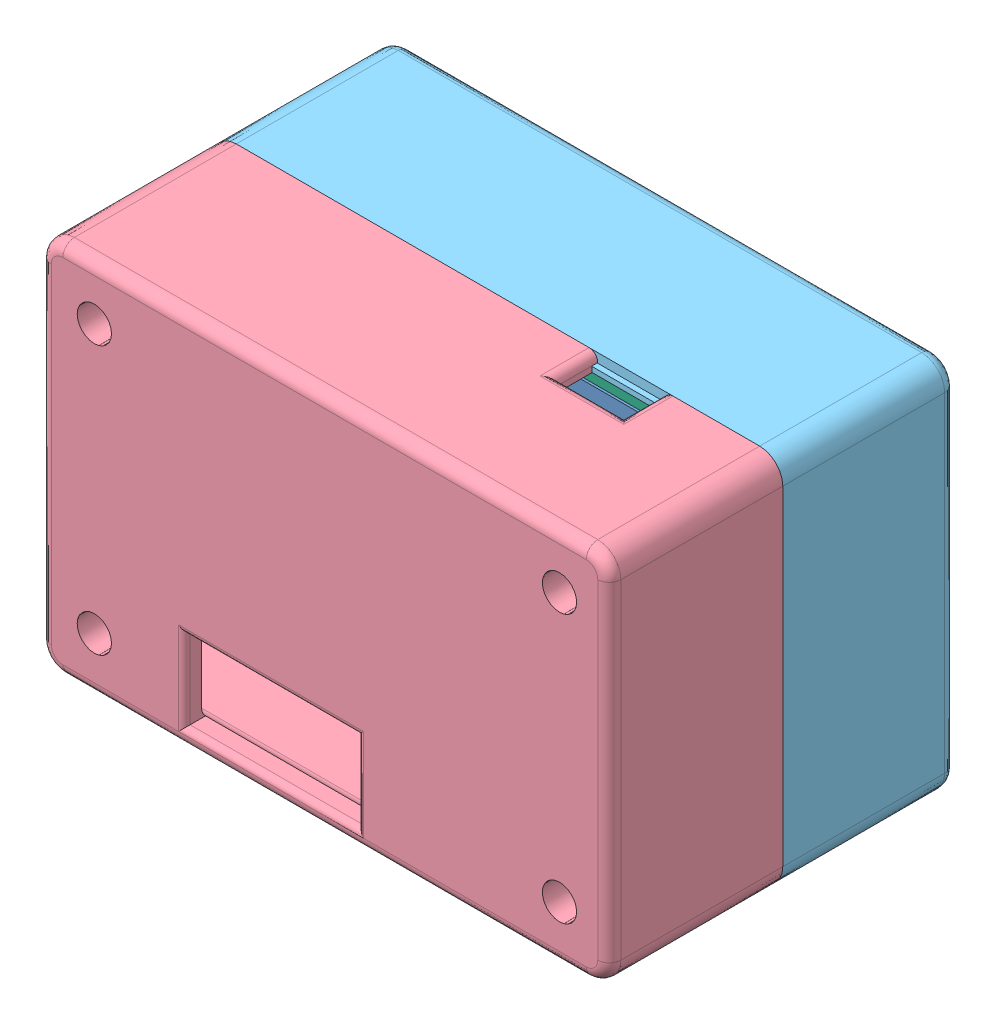
SolidWorks assembly final, configuration Default. Lengths in mm.
Overall size (268.32 64.99 60).
189 component instances, 44 part files, 14 mates.
Components (placement in the parent):
- PCB1.step-1: PCB1.step [Default] at origin size (88.64 54.99 37.9)
  - Board.step-1: Board.step [Default] at origin size (88.64 54.99 0.41)
    - Open CASCADE STEP translator 6.8 1.1.1.step-1: Open CASCADE STEP translator 6.8 1.1.1.step [Default] at (0 0 -0.4115) size (88.64 54.99 0.41)
  - J3.step-1: J3.step [Default] at origin size (11.2 7.5 13.4)
    - 691102710002.step-1: 691102710002.step [Default] at (107.7229 115.096 5.01) x (-1 0 0) z (0 0 1) size (11.2 7.5 13.4)
      - 691502710002.step-1: 691502710002.step [Default] at origin size (11.2 7.5 9.9)
      - 6911027100xx_CAGE.step-1: 6911027100xx_CAGE.step [Default] at (2.5 -0.45 -1.75) size (4 4 9.05)
      - 6911027100xx_CAGE.step-2: 6911027100xx_CAGE.step [Default] at (-2.5 -0.45 -1.75) size (4 4 9.05)
      - 6911027100xx_PIN.step-1: 6911027100xx_PIN.step [Default] at (2.5 -0.45 -0.3503) size (3.9 5.3 2.5)
      - 6911027100xx_PIN.step-2: 6911027100xx_PIN.step [Default] at (-2.5 -0.45 -0.3503) size (3.9 5.3 2.5)
      - 6911027100xx_VIS.step-1: 6911027100xx_VIS.step [Default] at (2.5 -0.45 4.2) x (0 -1 0) z (0 0 1) size (3.5 3.5 5.3)
      - 6911027100xx_VIS.step-2: 6911027100xx_VIS.step [Default] at (-2.5 -0.45 4.2) x (0 -1 0) z (0 0 1) size (3.5 3.5 5.3)
  - Ths.step-1: Ths.step [Default] at origin size (6.6 6.99 9.5)
    - 6050182896.step-1: 6050182896.step [Default] at (65.386 72.734 2.3) x (-1 0 0) z (0 0 1) size (6.6 6.99 9.5)
  - -V.step-1: -V.step [Default] at origin size (6.6 6.99 9.5)
    - 6050182896.step-1: 6050182896.step [Default] at (75.618 72.943 2.3) x (-1 0 0) z (0 0 1) size (6.6 6.99 9.5)
  - +V.step-1: +V.step [Default] at origin size (6.6 6.99 9.5)
    - 6050182896.step-1: 6050182896.step [Default] at (85.076 73.044 2.3) x (-1 0 0) z (0 0 1) size (6.6 6.99 9.5)
  - data.step-1: data.step [Default] at origin size (7.4 5.75 10.4)
    - 6050178176.step-1: 6050178176.step [Default] at (96.394 70.589 0) size (7.4 5.75 10.4)
      - Body.step-1: Body.step [Default] at origin size (7.4 5.75 7)
      - LeadsArray.step-1: LeadsArray.step [Default] at origin size (3.14 0.64 10.4)
  - power.step-1: power.step [Default] at origin size (5.75 9.9 10.4)
    - 6050171776.step-1: 6050171776.step [Default] at (61.311 101.996 -5.27) x (0 -1 0) z (-1 0 0) size (9.9 10.4 5.75)
  - C6.step-1: C6.step [Default] at origin size (5.59 4.41 14.72)
    - 6050182736.step-1: 6050182736.step [Default] at (52.118 71.908 0) size (5.59 4.41 14.72)
      - Body-0.step-1: Body-0.step [Default] at (0 0 0.1) size (4.41 4.41 9.62)
      - Leads.step-1: Leads.step [Default] at origin size (5.59 0.51 5.1)
      - Leads.step-2: Leads.step [Default] at origin size (5.59 0.51 5.1)
  - C5.step-1: C5.step [Default] at origin size (5.59 4.41 14.72)
    - 6050182736.step-1: 6050182736.step [Default] at (52.058 77.843 0) size (5.59 4.41 14.72)
      - Body-0.step-1: Body-0.step [Default] at (0 0 0.1) size (4.41 4.41 9.62)
      - Leads.step-1: Leads.step [Default] at origin size (5.59 0.51 5.1)
      - Leads.step-2: Leads.step [Default] at origin size (5.59 0.51 5.1)
  - 7905.step-1: 7905.step [Default] at origin size (4.6 10.2 37.42)
    - 6050176176.step-1: 6050176176.step [Default] at (47.866 81.132 0) x (0 1 0) z (0 0 1) size (10.2 4.6 37.42)
      - Tab.step-1: Tab.step [Default] at origin size (10.2 0.59 6.4)
      - Body-1.step-1: Body-1.step [Default] at (-2.4 -1.53 3.715) size (10.2 4.6 9.1)
      - PinsArray.step-1: PinsArray.step [Default] at origin size (6.52 0.59 21.91) (hidden)
  - R1.step-1: R1.step [Default] at origin size (2.6 16.5 5.2)
    - 6050177696.step-1: 6050177696.step [Default] at (64.173 88.049 0) x (0 1 0) z (0 0 1) size (16.5 2.6 5.2)
      - SimpleBody.step-1: SimpleBody.step [Default] at (4.8 0 1.3) x (0 0 -1) z (1 0 0) size (2.6 2.6 6.3)
      - Sweep1.step-1: Sweep1.step [Default] at origin size (5.1 0.6 4.2)
      - Sweep2.step-1: Sweep2.step [Default] at origin size (5.1 0.6 4.2)
  - C3.step-1: C3.step [Default] at origin size (5.59 4.41 14.72)
    - 6050182736.step-1: 6050182736.step [Default] at (66.929 82.931 0) size (5.59 4.41 14.72)
      - Body-0.step-1: Body-0.step [Default] at (0 0 0.1) size (4.41 4.41 9.62)
      - Leads.step-1: Leads.step [Default] at origin size (5.59 0.51 5.1)
      - Leads.step-2: Leads.step [Default] at origin size (5.59 0.51 5.1)
  - OP-amp.step-1: OP-amp.step [Default] at origin size (19.18 8.22 8.83)
    - 6050170576.step-1: 6050170576.step [Default] at (85.217 111.346 0) x (0 1 0) z (0 0 1) size (8.22 19.18 8.83)
      - Body-2.step-1: Body-2.step [Default] at origin size (6.6 19.18 4.37)
      - PinsArrayLR.step-1: PinsArrayLR.step [Default] at origin size (8.22 16.36 6.45)
  - Flip_flop.step-1: Flip_flop.step [Default] at origin size (19.69 7.87 8.37)
    - 6050177936.step-1: 6050177936.step [Default] at (103.645 80.451 2.6) x (0 1 0) z (1 0 0) size (7.87 8.37 19.69)
      - BODY_N0014A_AF0.step-1: BODY_N0014A_AF0.step [Default] at origin size (6.35 4.55 19.69)
      - LEAD_N0014A_AF1.step-1: LEAD_N0014A_AF1.step [Default] at (-3.175 0.127 -7.62) x (-1 0 0) z (0 0 -1) size (0.76 5.85 1.52)
      - LEAD_N0014A.step-1: LEAD_N0014A.step [Default] at (-3.175 0.127 -5.08) x (-1 0 0) z (0 0 -1) size (0.76 5.85 1.52)
      - LEAD_N0014A.step-2: LEAD_N0014A.step [Default] at (-3.175 0.127 -2.54) x (-1 0 0) z (0 0 -1) size (0.76 5.85 1.52)
      - LEAD_N0014A.step-3: LEAD_N0014A.step [Default] at (-3.175 0.127 0) x (-1 0 0) z (0 0 -1) size (0.76 5.85 1.52)
      - LEAD_N0014A.step-4: LEAD_N0014A.step [Default] at (-3.175 0.127 2.54) x (-1 0 0) z (0 0 -1) size (0.76 5.85 1.52)
      - LEAD_N0014A.step-5: LEAD_N0014A.step [Default] at (-3.175 0.127 5.08) x (-1 0 0) z (0 0 -1) size (0.76 5.85 1.52)
      - LEAD_N0014A_AF3.step-1: LEAD_N0014A_AF3.step [Default] at (-3.175 0.127 7.62) x (-1 0 0) z (0 0 -1) size (0.76 5.85 1.52)
      - LEAD_N0014A_AF0.step-1: LEAD_N0014A_AF0.step [Default] at (3.175 0.127 -7.62) size (0.76 5.85 1.52)
      - LEAD_N0014A.step-6: LEAD_N0014A.step [Default] at (3.175 0.127 -5.08) size (0.76 5.85 1.52)
      - LEAD_N0014A.step-7: LEAD_N0014A.step [Default] at (3.175 0.127 -2.54) size (0.76 5.85 1.52)
      - LEAD_N0014A.step-8: LEAD_N0014A.step [Default] at (3.175 0.127 0) size (0.76 5.85 1.52)
      - LEAD_N0014A.step-9: LEAD_N0014A.step [Default] at (3.175 0.127 2.54) size (0.76 5.85 1.52)
      - LEAD_N0014A.step-10: LEAD_N0014A.step [Default] at (3.175 0.127 5.08) size (0.76 5.85 1.52)
      - LEAD_N0014A_AF2.step-1: LEAD_N0014A_AF2.step [Default] at (3.175 0.127 7.62) size (0.76 5.85 1.52)
  - R4.step-1: R4.step [Default] at origin size (2.6 16.5 5.2)
    - 6050177696.step-1: 6050177696.step [Default] at (121.676 86.677 0) x (0 1 0) z (0 0 1) size (16.5 2.6 5.2)
      - SimpleBody.step-1: SimpleBody.step [Default] at (4.8 0 1.3) x (0 0 -1) z (1 0 0) size (2.6 2.6 6.3)
      - Sweep1.step-1: Sweep1.step [Default] at origin size (5.1 0.6 4.2)
      - Sweep2.step-1: Sweep2.step [Default] at origin size (5.1 0.6 4.2)
  - R3.step-1: R3.step [Default] at origin size (2.6 16.5 5.2)
    - 6050177696.step-1: 6050177696.step [Default] at (116.332 86.716 0) x (0 1 0) z (0 0 1) size (16.5 2.6 5.2)
      - SimpleBody.step-1: SimpleBody.step [Default] at (4.8 0 1.3) x (0 0 -1) z (1 0 0) size (2.6 2.6 6.3)
      - Sweep1.step-1: Sweep1.step [Default] at origin size (5.1 0.6 4.2)
      - Sweep2.step-1: Sweep2.step [Default] at origin size (5.1 0.6 4.2)
  - Q1.step-1: Q1.step [Default] at origin size (3.99 4.99 4.66)
    - 6126394224.step-1: 6126394224.step [Default] at (108.916 91.834 2.2) size (3.99 4.99 4.66)
      - Extruded.step-1: Extruded.step [Default] at origin size (3.99 4.99 4.66)
  - D4.step-1: D4.step [Default] at origin size (2.7 14.91 5.4)
    - 6050182656.step-1: 6050182656.step [Default] at (92.644 87.792 0) x (0 1 0) z (0 0 1) size (14.91 2.7 5.4)
      - Body-3.step-1: Body-3.step [Default] at (4.7 0 1.35) x (0 0 -1) z (1 0 0) size (2.7 2.7 4.65)
      - Sweep1-4.step-1: Sweep1-4.step [Default] at origin size (5.13 0.86 4.48)
      - Sweep2-5.step-1: Sweep2-5.step [Default] at origin size (5.13 0.86 4.48)
  - D3.step-1: D3.step [Default] at origin size (2.7 14.91 5.4)
    - 6050182656.step-1: 6050182656.step [Default] at (86.802 87.668 0) x (0 1 0) z (0 0 1) size (14.91 2.7 5.4)
      - Body-3.step-1: Body-3.step [Default] at (4.7 0 1.35) x (0 0 -1) z (1 0 0) size (2.7 2.7 4.65)
      - Sweep1-4.step-1: Sweep1-4.step [Default] at origin size (5.13 0.86 4.48)
      - Sweep2-5.step-1: Sweep2-5.step [Default] at origin size (5.13 0.86 4.48)
  - D2.step-1: D2.step [Default] at origin size (2.7 14.91 5.4)
    - 6050182656.step-1: 6050182656.step [Default] at (98.425 88.008 0) x (0 1 0) z (0 0 1) size (14.91 2.7 5.4)
      - Body-3.step-1: Body-3.step [Default] at (4.7 0 1.35) x (0 0 -1) z (1 0 0) size (2.7 2.7 4.65)
      - Sweep1-4.step-1: Sweep1-4.step [Default] at origin size (5.13 0.86 4.48)
      - Sweep2-5.step-1: Sweep2-5.step [Default] at origin size (5.13 0.86 4.48)
  - D1.step-1: D1.step [Default] at origin size (2.7 14.91 5.4)
    - 6050182656.step-1: 6050182656.step [Default] at (103.632 87.881 0) x (0 1 0) z (0 0 1) size (14.91 2.7 5.4)
      - Body-3.step-1: Body-3.step [Default] at (4.7 0 1.35) x (0 0 -1) z (1 0 0) size (2.7 2.7 4.65)
      - Sweep1-4.step-1: Sweep1-4.step [Default] at origin size (5.13 0.86 4.48)
      - Sweep2-5.step-1: Sweep2-5.step [Default] at origin size (5.13 0.86 4.48)
  - clock.step-1: clock.step [Default] at origin size (7.89 10.15 6.68)
    - 6126399104.step-1: 6126399104.step [Default] at (77.785 91.732 0.51) size (6.6 10.15 4.57)
      - Extruded-6.step-1: Extruded-6.step [Default] at origin size (6.6 10.15 4.57)
    - 6126398704.step-1: 6126398704.step [Default] at (81.595 95.542 -1.6) size (0.27 0.72 1.6)
      - Extruded-7.step-1: Extruded-7.step [Default] at origin size (0.27 0.72 1.6)
    - 6126398304.step-1: 6126398304.step [Default] at (81.4075 95.542 2.66) size (0.64 1 0.27)
      - Extruded-8.step-1: Extruded-8.step [Default] at origin size (0.64 1 0.27)
    - 6126397904.step-1: 6126397904.step [Default] at (81.595 95.542 0) size (0.27 1 2.66)
      - Extruded-9.step-1: Extruded-9.step [Default] at origin size (0.27 1 2.66)
    - 6126398704.step-2: 6126398704.step [Default] at (81.595 93.002 -1.6) size (0.27 0.72 1.6)
      - Extruded-7.step-1: Extruded-7.step [Default] at origin size (0.27 0.72 1.6)
    - 6126398304.step-2: 6126398304.step [Default] at (81.4075 93.002 2.66) size (0.64 1 0.27)
      - Extruded-8.step-1: Extruded-8.step [Default] at origin size (0.64 1 0.27)
    - 6126397904.step-2: 6126397904.step [Default] at (81.595 93.002 0) size (0.27 1 2.66)
      - Extruded-9.step-1: Extruded-9.step [Default] at origin size (0.27 1 2.66)
    - 6126398704.step-3: 6126398704.step [Default] at (81.595 90.462 -1.6) size (0.27 0.72 1.6)
      - Extruded-7.step-1: Extruded-7.step [Default] at origin size (0.27 0.72 1.6)
    - 6126398304.step-3: 6126398304.step [Default] at (81.4075 90.462 2.66) size (0.64 1 0.27)
      - Extruded-8.step-1: Extruded-8.step [Default] at origin size (0.64 1 0.27)
    - 6126397904.step-3: 6126397904.step [Default] at (81.595 90.462 0) size (0.27 1 2.66)
      - Extruded-9.step-1: Extruded-9.step [Default] at origin size (0.27 1 2.66)
    - 6126398704.step-4: 6126398704.step [Default] at (81.595 87.922 -1.6) size (0.27 0.72 1.6)
      - Extruded-7.step-1: Extruded-7.step [Default] at origin size (0.27 0.72 1.6)
    - 6126398304.step-4: 6126398304.step [Default] at (81.4075 87.922 2.66) size (0.64 1 0.27)
      - Extruded-8.step-1: Extruded-8.step [Default] at origin size (0.64 1 0.27)
    - 6126397904.step-4: 6126397904.step [Default] at (81.595 87.922 0) size (0.27 1 2.66)
      - Extruded-9.step-1: Extruded-9.step [Default] at origin size (0.27 1 2.66)
    - 6126398704.step-5: 6126398704.step [Default] at (73.975 87.922 -1.6) size (0.27 0.72 1.6)
      - Extruded-7.step-1: Extruded-7.step [Default] at origin size (0.27 0.72 1.6)
    - 6126398304.step-5: 6126398304.step [Default] at (74.1625 87.922 2.66) size (0.64 1 0.27)
      - Extruded-8.step-1: Extruded-8.step [Default] at origin size (0.64 1 0.27)
    - 6126397904.step-5: 6126397904.step [Default] at (73.975 87.922 0) size (0.27 1 2.66)
      - Extruded-9.step-1: Extruded-9.step [Default] at origin size (0.27 1 2.66)
    - 6126398704.step-6: 6126398704.step [Default] at (73.975 90.462 -1.6) size (0.27 0.72 1.6)
      - Extruded-7.step-1: Extruded-7.step [Default] at origin size (0.27 0.72 1.6)
    - 6126398304.step-6: 6126398304.step [Default] at (74.1625 90.462 2.66) size (0.64 1 0.27)
      - Extruded-8.step-1: Extruded-8.step [Default] at origin size (0.64 1 0.27)
    - 6126397904.step-6: 6126397904.step [Default] at (73.975 90.462 0) size (0.27 1 2.66)
      - Extruded-9.step-1: Extruded-9.step [Default] at origin size (0.27 1 2.66)
    - 6126398704.step-7: 6126398704.step [Default] at (73.975 93.002 -1.6) size (0.27 0.72 1.6)
      - Extruded-7.step-1: Extruded-7.step [Default] at origin size (0.27 0.72 1.6)
    - 6126398304.step-7: 6126398304.step [Default] at (74.1625 93.002 2.66) size (0.64 1 0.27)
      - Extruded-8.step-1: Extruded-8.step [Default] at origin size (0.64 1 0.27)
    - 6126397904.step-7: 6126397904.step [Default] at (73.975 93.002 0) size (0.27 1 2.66)
      - Extruded-9.step-1: Extruded-9.step [Default] at origin size (0.27 1 2.66)
    - 6126398704.step-8: 6126398704.step [Default] at (73.975 95.542 -1.6) size (0.27 0.72 1.6)
      - Extruded-7.step-1: Extruded-7.step [Default] at origin size (0.27 0.72 1.6)
    - 6126398304.step-8: 6126398304.step [Default] at (74.1625 95.542 2.66) size (0.64 1 0.27)
      - Extruded-8.step-1: Extruded-8.step [Default] at origin size (0.64 1 0.27)
    - 6126397904.step-8: 6126397904.step [Default] at (73.975 95.542 0) size (0.27 1 2.66)
      - Extruded-9.step-1: Extruded-9.step [Default] at origin size (0.27 1 2.66)
  - R2.step-1: R2.step [Default] at origin size (2.6 16.5 5.2)
    - 6050177696.step-1: 6050177696.step [Default] at (58.166 88.113 0) x (0 1 0) z (0 0 1) size (16.5 2.6 5.2)
      - SimpleBody.step-1: SimpleBody.step [Default] at (4.8 0 1.3) x (0 0 -1) z (1 0 0) size (2.6 2.6 6.3)
      - Sweep1.step-1: Sweep1.step [Default] at origin size (5.1 0.6 4.2)
      - Sweep2.step-1: Sweep2.step [Default] at origin size (5.1 0.6 4.2)
  - C4.step-1: C4.step [Default] at origin size (5.59 4.41 14.72)
    - 6050175056.step-1: 6050175056.step [Default] at (62.467 83.051 0) x (-1 0 0) z (0 0 1) size (5.59 4.41 14.72)
      - Body-10.step-1: Body-10.step [Default] at (0 0 0.1) size (4.41 4.41 9.62)
      - Leads-11.step-1: Leads-11.step [Default] at origin size (5.59 0.51 5.1)
      - Leads-11.step-2: Leads-11.step [Default] at origin size (5.59 0.51 5.1)
  - reg.step-1: reg.step [Default] at origin size (10.5 4.7 16.2)
    - 6126393744.step-1: 6126393744.step [Default] at (58.166 110.576 13.05) size (10.4 1.3 6.65)
      - Extruded-12.step-1: Extruded-12.step [Default] at origin size (10.4 1.3 6.65)
    - 6126393424.step-1: 6126393424.step [Default] at (58.166 112.226 3.5) size (10.5 4.7 9.55)
      - Extruded-13.step-1: Extruded-13.step [Default] at origin size (10.5 4.7 9.55)
  - C2.step-1: C2.step [Default] at origin size (4.41 5.59 14.72)
    - 6050181776.step-1: 6050181776.step [Default] at (67.177 109.168 0) x (0 1 0) z (0 0 1) size (5.59 4.41 14.72)
      - Body-14.step-1: Body-14.step [Default] at (0 0 0.1) size (4.41 4.41 9.62)
      - Leads-15.step-1: Leads-15.step [Default] at origin size (5.59 0.51 5.1)
      - Leads-15.step-2: Leads-15.step [Default] at origin size (5.59 0.51 5.1)
  - C1.step-1: C1.step [Default] at origin size (4.41 5.59 14.72)
    - 6050181776.step-1: 6050181776.step [Default] at (48.081 108.31 0) x (0 1 0) z (0 0 1) size (5.59 4.41 14.72)
      - Body-14.step-1: Body-14.step [Default] at (0 0 0.1) size (4.41 4.41 9.62)
      - Leads-15.step-1: Leads-15.step [Default] at origin size (5.59 0.51 5.1)
      - Leads-15.step-2: Leads-15.step [Default] at origin size (5.59 0.51 5.1)
- Part41^final-1: Part41^final [Default] at (0 0 -0.4115) x (-1 0 0) z (0 0 -1) size (98.5 64.99 30) (virtual)
- Part45^final-1: Part45^final [Default] at (0 0 -0.4115) x (-1 0 0) z (0 0 -1) size (98.5 64.99 30.97) (virtual)
- 9V_Batterie.STEP-1: 9V_Batterie.STEP [Default] at (99.8105 76.793 -17.6615) x (1 0 0) z (0 1 0) size (26.5 17.5 49.69)
  - Corps Batterie.STEP-1: Corps Batterie.STEP [Default] at origin size (26.5 17.5 45.5)
  - Connecteur femelle Batterie 9V.STEP-1: Connecteur femelle Batterie 9V.STEP [Default] at (-6.5 0 0.5) x (1 0 0) z (0 1 0) size (8.01 5.32 8.38)
  - Connecteur male Batterie 9V.STEP-1: Connecteur male Batterie 9V.STEP [Default] at (6.5 0 0.5) x (0.847736 0.530419 0) z (-0.530419 0.847736 0) size (7.01 4.82 7.01)
- 9V_Batterie.STEP-2: 9V_Batterie.STEP [Default] at (69.3105 76.793 -17.6615) x (1 0 0) z (0 1 0) size (26.5 17.5 49.69)
  - Corps Batterie.STEP-1: Corps Batterie.STEP [Default] at origin size (26.5 17.5 45.5)
  - Connecteur femelle Batterie 9V.STEP-1: Connecteur femelle Batterie 9V.STEP [Default] at (-6.5 0 0.5) x (1 0 0) z (0 1 0) size (8.01 5.32 8.38)
  - Connecteur male Batterie 9V.STEP-1: Connecteur male Batterie 9V.STEP [Default] at (6.5 0 0.5) x (0.847736 0.530419 0) z (-0.530419 0.847736 0) size (7.01 4.82 7.01)
Mates (geometry in assembly coordinates):
- InPlace2: in place: plane of PCB1.step-1/Board.step-1/Open CASCADE STEP translator 6.8 1.1.1.step-1 through (40.517 121.793 -0.4115) normal (0 0 -1); plane of ? through (0 0 -0.4115) normal (0 0 -1); moOrthogonalPlaneRef_w of PCB1.step-1/Board.step-1/Open CASCADE STEP translator 6.8 1.1.1.step-1 through (40.517 121.793 -0.4115) normal (0 0 -1); plane of ? through (0 0 -0.4115) normal (0 1 0); plane of PCB1.step-1/Board.step-1/Open CASCADE STEP translator 6.8 1.1.1.step-1 through (40.517 121.793 -0.4115) normal (0 0 -1); plane of ? through (0 0 -0.4115) normal (-1 0 0); plane of PCB1.step-1/Board.step-1/Open CASCADE STEP translator 6.8 1.1.1.step-1 through (40.517 121.793 -0.4115) normal (0 0 -1); unknown of ?
- Coincident4: coincident aligned: plane of ?; plane of ?
- Coincident5: coincident aligned: moOrthogonalPlaneRef_w of PCB1.step-1/Board.step-1/Open CASCADE STEP translator 6.8 1.1.1.step-1 through (0 0 -0.4115) normal (0 1 0); plane of Part41^PCB1-1 through (0 0 -0.4115) normal (0 1 0)
- Coincident6: coincident anti-aligned: moOrthogonalPlaneRef_w of PCB1.step-1/Board.step-1/Open CASCADE STEP translator 6.8 1.1.1.step-1 through (0 0 -0.4115) normal (1 0 0); plane of Part41^PCB1-1 through (0 0 -0.4115) normal (-1 0 0)
- InPlace4: in place: plane of ? through (0 0 -0.4115) normal (0 0 -1); plane of ? through (0 0 -0.4115) normal (0 0 -1); plane of ? through (0 0 -0.4115) normal (0 0 -1); plane of ? through (0 0 -0.4115) normal (0 1 0); plane of ? through (0 0 -0.4115) normal (0 0 -1); plane of ? through (0 0 -0.4115) normal (-1 0 0); plane of ? through (0 0 -0.4115) normal (0 0 -1); unknown of ?
- Coincident10: coincident aligned: plane of ?; plane of ?
- Coincident11: coincident aligned: moOrthogonalPlaneRef_w of Part41^PCB1-1 through (0 0 -0.4115) normal (0 1 0); plane of Part45^PCB1-1 through (0 0 -0.4115) normal (0 1 0)
- Coincident12: coincident anti-aligned: moOrthogonalPlaneRef_w of Part41^PCB1-1 through (0 0 -0.4115) normal (1 0 0); plane of Part45^PCB1-1 through (0 0 -0.4115) normal (-1 0 0)
- Coincident13: coincident anti-aligned: plane of Part45^PCB1-1 through (0 0 -26.4115) normal (0 0 1); plane of 9V_Batterie.STEP-1/Corps Batterie.STEP-1 through (99.8105 122.293 -26.4115) normal (0 0 -1)
- Distance1: distance = 18.5985 mm anti-aligned: plane of 9V_Batterie.STEP-1/Corps Batterie.STEP-1 through (113.0605 122.293 -17.6615) normal (1 0 0); plane of Part45^PCB1-1 through (131.659 124.293 -26.4115) normal (-1 0 0)
- Coincident15: coincident anti-aligned: plane of Part45^PCB1-1 through (0 0 -26.4115) normal (0 0 1); plane of 9V_Batterie.STEP-2/Corps Batterie.STEP-1 through (69.3105 122.293 -26.4115) normal (0 0 -1)
- Distance2: distance = 4 mm anti-aligned: plane of 9V_Batterie.STEP-1/Corps Batterie.STEP-1 through (86.5605 122.293 -17.6615) normal (-1 0 0); plane of 9V_Batterie.STEP-2/Corps Batterie.STEP-1 through (82.5605 122.293 -17.6615) normal (1 0 0)
- Coincident18: coincident aligned: plane of 9V_Batterie.STEP-1/Corps Batterie.STEP-1 through (99.8105 122.293 -17.6615) normal (0 1 0); plane of 9V_Batterie.STEP-2/Corps Batterie.STEP-1 through (69.3105 122.293 -17.6615) normal (0 1 0)
- Distance3: distance = 2 mm anti-aligned: plane of 9V_Batterie.STEP-1/Corps Batterie.STEP-1 through (99.8105 122.293 -17.6615) normal (0 1 0); plane of Part45^PCB1-1 through (131.659 124.293 -26.4115) normal (0 -1 0)
